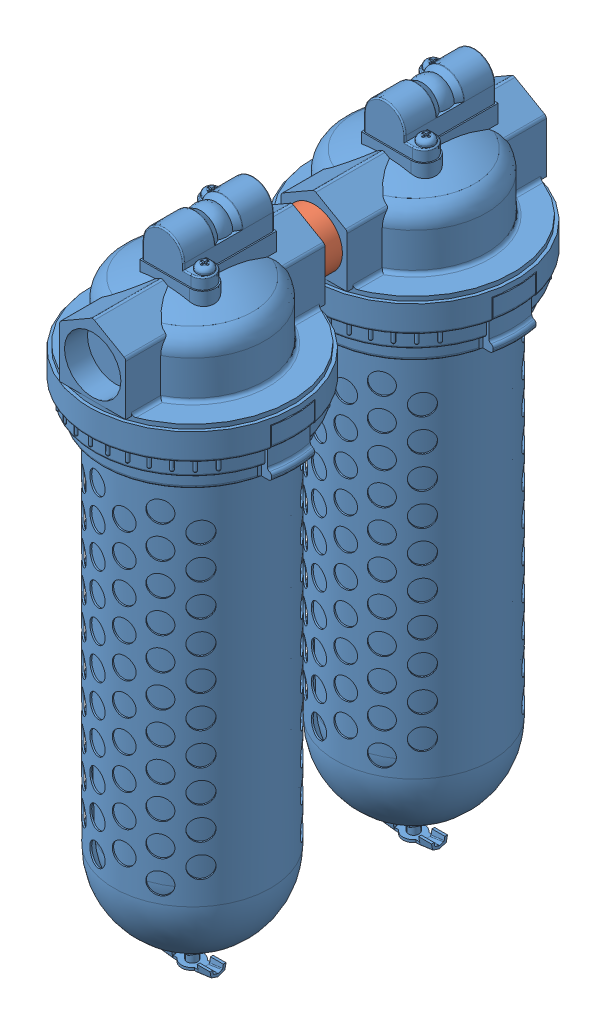
SolidWorks assembly ReadingTech_4P-090-P08-DCPi, configuration Default. Lengths in mm.
Overall size (121.86 385.36 252.73).
3 component instances, 2 part files, 3 mates.
Components (placement in the parent):
- ReadingTech_3P-090-P08-Pi-1: ReadingTech_3P-090-P08-Pi [Default] at (-12.6902 -232.2913 -2.3346) size (121.86 385.36 121.67)
- ReadingTech_3P-090-P08-Pi-2: ReadingTech_3P-090-P08-Pi [Default] at (-12.6902 -232.2913 -133.3986) size (121.86 385.36 121.67)
- ReadingTech- 90,150cfm_connector_1in-1: ReadingTech- 90,150cfm_connector_1in [Default] at (-12.6902 156.7097 -61.2626) x (1 0 0) z (0 1 0) size (33.4 13.21 33.4)
Mates (geometry in assembly coordinates):
- Coincident1: coincident anti-aligned: circle of ReadingTech_3P-090-P08-Pi-2; circle of ReadingTech- 90,150cfm_connector_1in-1
- Coincident2: coincident aligned: circle of ReadingTech_3P-090-P08-Pi-1; circle of ReadingTech- 90,150cfm_connector_1in-1
- Coincident3: coincident aligned: plane of ReadingTech_3P-090-P08-Pi-1 through (6.8678 169.4097 56.5934) normal (1 0 0); plane of ReadingTech_3P-090-P08-Pi-2 through (6.8678 169.4097 -74.4706) normal (1 0 0)
